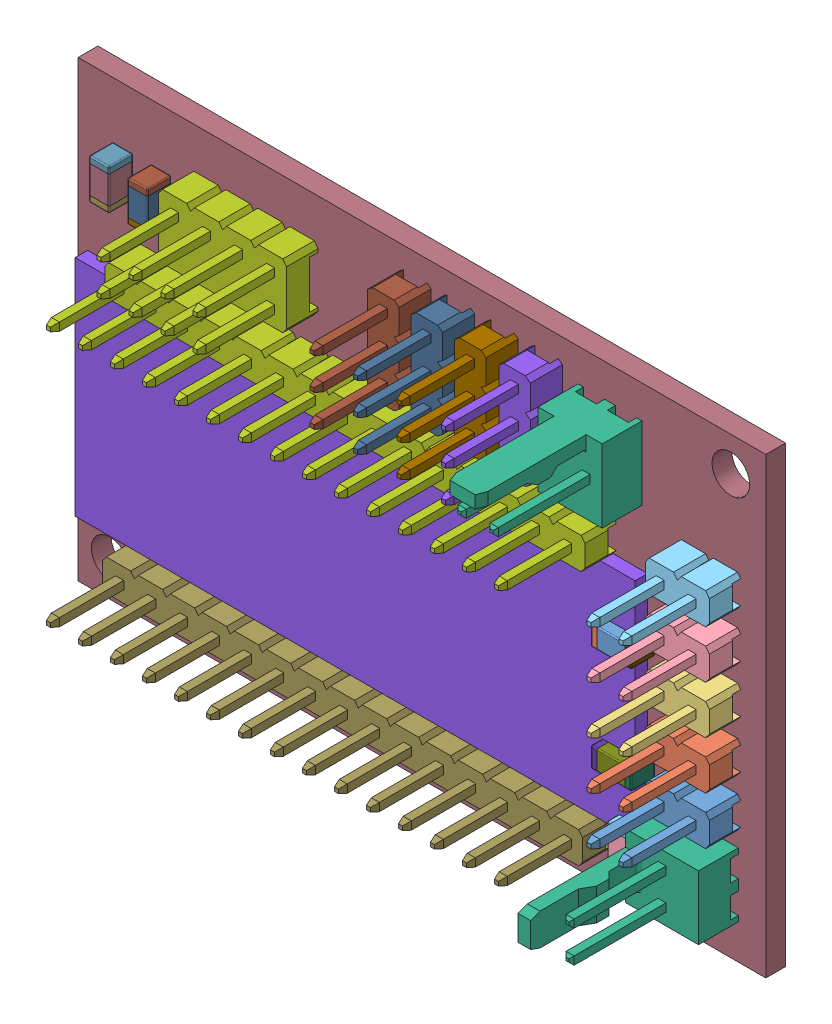
SolidWorks assembly ReceiverCircuit, configuration Default. Lengths in mm.
Overall size (54.59 35.99 15.26).
31 component instances, 31 part files, 0 mates.
Components (placement in the parent):
- 1-1: 1 [Default] at (50.7746 10.287 1.57) size (5.08 2.5 11.2)
- 1001-1: 1001 [Default] at (50.7746 14.097 1.57) size (5.08 2.5 11.2)
- 1002-1: 1002 [Default] at (50.7746 17.907 1.57) size (5.08 2.5 11.2)
- 1003-1: 1003 [Default] at (50.7746 21.717 1.57) size (5.08 2.5 11.2)
- 1004-1: 1004 [Default] at (50.7746 25.527 1.57) size (5.08 2.5 11.2)
- =_[0_1_1_2]-1: =_[0_1_1_2] [Default] at (43.0022 30.5054 1.57) size (5.08 5.8 15.26)
- 1005-1: 1005 [Default] at (24.384 24.384 1.57) size (38.1 2.5 11.2)
- Component_1-1: Component_1 [Default] at (26.924 14.224 1.57) size (44.45 17.78 1)
- CAPC3216X191-1: CAPC3216X191 [Default] at (7.366 29.972 1.57) x (0 -1 0) z (0 0 1) size (0.5 1.6 1.9)
- CAPC3216X192-1: CAPC3216X192 [Default] at (7.366 29.972 1.57) x (0 -1 0) z (0 0 1) size (2.2 1.6 1.9)
- CAPC3216X190-1: CAPC3216X190 [Default] at (7.366 29.972 1.57) x (0 -1 0) z (0 0 1) size (0.5 1.6 1.9)
- CAPC3216X193-1: CAPC3216X193 [Default] at (4.318 29.972 1.57) x (0 -1 0) z (0 0 1) size (0.5 1.6 1.9)
- CAPC3216X194-1: CAPC3216X194 [Default] at (4.318 29.972 1.57) x (0 -1 0) z (0 0 1) size (2.2 1.6 1.9)
- CAPC3216X195-1: CAPC3216X195 [Default] at (4.318 29.972 1.57) x (0 -1 0) z (0 0 1) size (0.5 1.6 1.9)
- CAPC3216X196-1: CAPC3216X196 [Default] at (44.958 10.16 1.57) size (0.5 1.6 1.9)
- CAPC3216X197-1: CAPC3216X197 [Default] at (44.958 10.16 1.57) size (2.2 1.6 1.9)
- CAPC3216X198-1: CAPC3216X198 [Default] at (44.958 10.16 1.57) size (0.5 1.6 1.9)
- CAPC3216X199-1: CAPC3216X199 [Default] at (44.958 18.542 1.57) size (0.5 1.6 1.9)
- CAPC3216X200-1: CAPC3216X200 [Default] at (44.958 18.542 1.57) size (2.2 1.6 1.9)
- CAPC3216X201-1: CAPC3216X201 [Default] at (44.958 18.542 1.57) size (0.5 1.6 1.9)
- CAPC3216X202-1: CAPC3216X202 [Default] at (45.466 4.826 1.57) x (0 -1 0) z (0 0 1) size (0.5 1.6 1.9)
- CAPC3216X203-1: CAPC3216X203 [Default] at (45.466 4.826 1.57) x (0 -1 0) z (0 0 1) size (2.2 1.6 1.9)
- CAPC3216X204-1: CAPC3216X204 [Default] at (45.466 4.826 1.57) x (0 -1 0) z (0 0 1) size (0.5 1.6 1.9)
- =_[0_1_1_2]001-1: =_[0_1_1_2]001 [Default] at (50.292 5.334 1.57) x (0 1 0) z (0 0 1) size (5.08 5.8 15.26)
- 1006-1: 1006 [Default] at (14.732 30.226 1.57) size (10.16 5.08 11.5)
- 1007-1: 1007 [Default] at (37.9476 30.6832 1.57) x (0 -1 0) z (0 0 1) size (7.62 2.5 11.2)
- 1008-1: 1008 [Default] at (34.4424 30.6832 1.57) x (0 -1 0) z (0 0 1) size (7.62 2.5 11.2)
- 1009-1: 1009 [Default] at (30.988 30.6832 1.57) x (0 -1 0) z (0 0 1) size (7.62 2.5 11.2)
- 1010-1: 1010 [Default] at (27.5336 30.6832 1.57) x (0 -1 0) z (0 0 1) size (7.62 2.5 11.2)
- 1011-1: 1011 [Default] at (24.384 4.064 1.57) x (-1 0 0) z (0 0 1) size (38.1 2.5 11.2)
- Component_Component-1: Component_Component [Default] at origin size (54.59 35.99 1.57)
